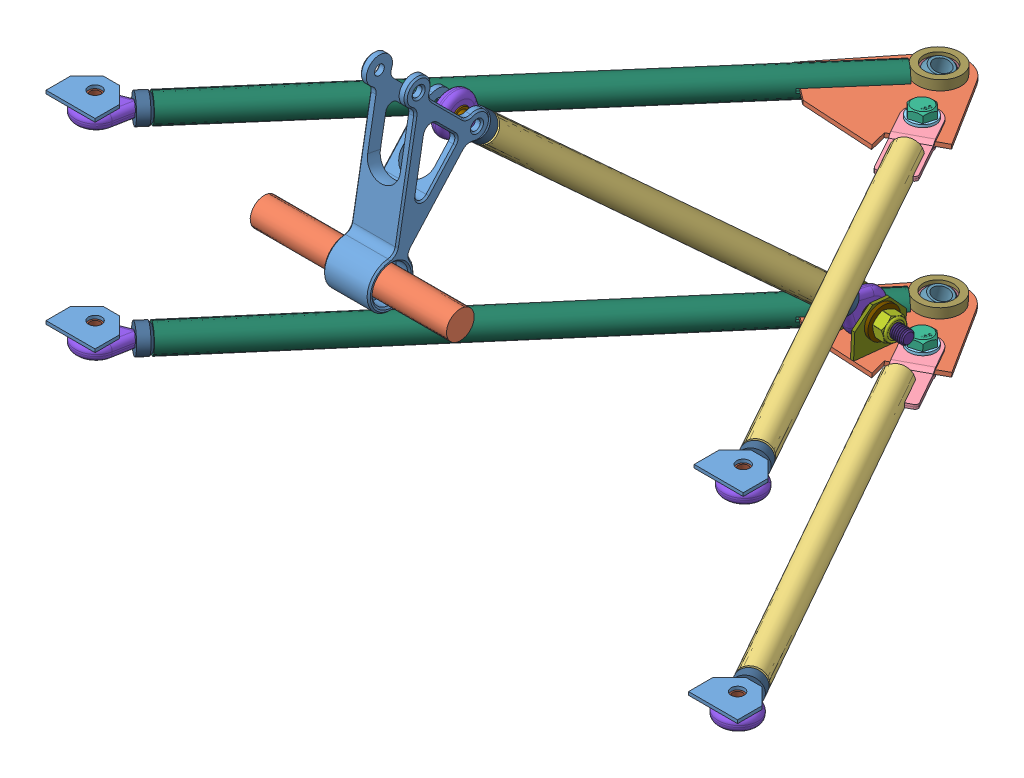
SolidWorks assembly Control Arms, Pushord, Bellcrank V6, configuration Default. Lengths in mm.
Overall size (449.35 312.63 431.67).
68 component instances, 21 part files, 29 mates.
Components (placement in the parent):
- frame connectors-10: frame connectors [Default] at (-357.6393 7.7366 39.1204) size (30 2 25)
- frame connectors-11: frame connectors [Default] at (38.6473 7.7366 39.1204) size (30 2 25)
- Upper Control Arm Assembly-1: Upper Control Arm Assembly [Default] at (-133.4882 -138.5087 -252.114) x (0.998299 0.002948 0.058228) z (-0.058303 0.05048 0.997022) size (425.46 42.68 337.86) (flexible)
  - Front Control Arm Plate-1: Front Control Arm Plate [Default] at origin size (91 2.5 76.52)
  - Rear Upper Control Arm-2: Rear Upper Control Arm [Default] at (102.2777 0 156.6502) x (-0.554844 0 -0.831954) z (0.831954 0 -0.554844) size (250 16 16)
  - Control Arm Link Plate-1: Control Arm Link Plate [Default] at (31.8652 1.25 43.6848) x (-0.554844 0 -0.831954) z (0.831954 0 -0.554844) size (54.1 2.5 20)
  - Control Arm Link Plate-2: Control Arm Link Plate [Default] at (31.8652 -1.25 43.6848) x (-0.554844 0 -0.831954) z (-0.831954 0 0.554844) size (54.1 2.5 20)
  - plain washer normal grade a_iso-1: plain washer normal grade a_iso [Washer ISO 7089 - 8] at (22.4051 2.5 29.5) x (0 -1 0) z (0.774417 0 0.632675) size (1.6 16 16)
  - 94863A205_High-Strength Class 10.9 Steel Hex Head Screw-1: 94863A205_High-Strength Class 10.9 Steel Hex Head Screw [94863A205] at (22.4051 4.1 29.5) x (0.632675 0 -0.774417) z (0 1 0) size (13 16.35 25.89)
  - 94645A111_High-Strength Steel Nylon-Insert Locknut-1: 94645A111_High-Strength Steel Nylon-Insert Locknut [94645A111] at (22.4051 -6.5 29.5) x (-0.772532 0 -0.634976) z (-0.634976 0 0.772532) size (13 8 14.93)
  - Link Insert Assembly-1: Link Insert Assembly [Default] at (147.8527 41.9532 248.8394) x (0.831954 0 -0.554844) z (0 -1 0) size (24 54 13.75) (flexible)
    - Link-1: Link [Default] at (13.2343 18.3157 41.9532) size (24 54 13.75)
    - Spherical Bearing Ball-1: Spherical Bearing Ball [Default] at (13.2343 47.8157 41.9532) x (0.025556 -0.043633 0.998721) z (0.479285 -0.876203 -0.050544) size (9 13.75 13.75)
  - Control Arm Insert-1: Control Arm Insert [Default] at (158.7294 0 241.2961) x (-0.831525 0.032128 0.554558) z (0.026729 0.999484 -0.017826) size (16 25 16)
  - 8mm Spehrical Bearing Insert-1: 8mm Spehrical Bearing Insert [Default] at (185.4125 6.4917 281.6051) x (0.944963 0.013733 -0.326889) z (-0.327164 0.048665 -0.943714) size (11 9 11)
  - Spherical Bearing Seat-1: Spherical Bearing Seat [Default] at (0 -0.3 0) size (30 15.1 30)
  - Wide Spherical Bearing-1: Wide Spherical Bearing [Default] at (-7.3247 -16.3877 13.3464) x (1 0 0) z (0 1 0) size (28.8 26.7 19.61) (flexible)
    - Wide Bearing Cage-1: Wide Bearing Cage [Default] at (7.3247 13.3464 16.0877) size (22 22 10.5)
    - Wide Ball-1: Wide Ball [Default] at (7.3247 13.3464 16.0877) x (-0.815772 0.552249 0.171862) z (0.221159 0.02328 0.97496) size (19.04 19.04 14)
  - Front Upper Control Arm-1: Front Upper Control Arm [Default] at (-100.6334 0 146.8287) x (0.559193 0 -0.829038) z (0.829038 0 0.559193) size (330 16 16)
  - Link Insert Assembly-2: Link Insert Assembly [Default] at (-191.0018 41.9532 257.1385) x (0.829038 0 0.559193) z (0 -1 0) size (24 54 13.75) (flexible)
    - Link-1: Link [Default] at (13.2343 18.3157 41.9532) size (24 54 13.75)
    - Spherical Bearing Ball-1: Spherical Bearing Ball [Default] at (13.2343 47.8157 41.9532) x (-0.030672 -0.040201 0.998721) z (-0.682409 -0.729237 -0.050311) size (9 13.75 13.75)
  - Control Arm Insert-2: Control Arm Insert [Default] at (-179.8953 0 264.3393) x (-0.82861 0.032128 -0.558904) z (0.026635 0.999484 0.017966) size (16 25 16)
  - 8mm Spehrical Bearing Insert-2: 8mm Spehrical Bearing Insert [Default] at (-206.7491 6.4917 304.5081) x (-0.995047 0.007946 -0.099088) z (-0.099363 -0.049938 0.993797) size (11 9 11)
  - Push Rod Upper Control Arm Bracket-1: Push Rod Upper Control Arm Bracket [Default] at (10.7762 13.75 44.5) x (0 0 1) z (0 -1 0) size (30 2 25)
  - Push Rod Upper Control Arm Bracket-2: Push Rod Upper Control Arm Bracket [Default] at (-11.2238 13.75 44.5) x (0 0 1) z (0 -1 0) size (30 2 25)
- frame connectors-14: frame connectors [Default] at (-357.6393 -114.2634 39.1204) size (30 2 25)
- frame connectors-15: frame connectors [Default] at (35.1906 -114.2634 39.1204) size (30 2 25)
- Lower Control Arm Assembly-4: Lower Control Arm Assembly [Default] at (-132.0035 -16.4507 -250.9682) x (0.997989 0.003206 0.063314) z (-0.063395 0.050464 0.996712) size (428.79 25.89 337.86) (flexible)
  - Front Control Arm Plate-1: Front Control Arm Plate [Default] at origin size (91 2.5 76.52)
  - Rear Upper Control Arm-2: Rear Upper Control Arm [Default] at (105.6055 0 154.4308) x (-0.554844 0 -0.831954) z (0.831954 0 -0.554844) size (250 16 16)
  - Control Arm Link Plate-1: Control Arm Link Plate [Default] at (31.8652 1.25 43.6848) x (-0.554844 0 -0.831954) z (0.831954 0 -0.554844) size (54.1 2.5 20)
  - Control Arm Link Plate-2: Control Arm Link Plate [Default] at (31.8652 -1.25 43.6848) x (-0.554844 0 -0.831954) z (-0.831954 0 0.554844) size (54.1 2.5 20)
  - plain washer normal grade a_iso-1: plain washer normal grade a_iso [Washer ISO 7089 - 8] at (22.4051 2.5 29.5) x (0 -1 0) z (0.774417 0 0.632675) size (1.6 16 16)
  - 94863A205_High-Strength Class 10.9 Steel Hex Head Screw-1: 94863A205_High-Strength Class 10.9 Steel Hex Head Screw [94863A205] at (22.4051 4.1 29.5) x (0.632675 0 -0.774417) z (0 1 0) size (13 16.35 25.89)
  - 94645A111_High-Strength Steel Nylon-Insert Locknut-1: 94645A111_High-Strength Steel Nylon-Insert Locknut [94645A111] at (22.4051 -6.5 29.5) x (-0.783807 0 -0.621005) z (-0.621005 0 0.783807) size (13 8 14.93)
  - Link Insert Assembly-1: Link Insert Assembly [Default] at (151.1806 41.9532 246.62) x (0.831954 0 -0.554844) z (0 -1 0) size (24 54 13.75) (flexible)
    - Link-1: Link [Default] at (13.2343 18.3157 41.9532) size (24 54 13.75)
    - Spherical Bearing Ball-1: Spherical Bearing Ball [Default] at (13.2343 47.8157 41.9532) x (0.025333 -0.043762 0.998721) z (-0.222587 0.973715 0.048313) size (9 13.75 13.75)
  - Control Arm Insert-1: Control Arm Insert [Default] at (162.0573 0 239.0767) x (-0.831525 0.032128 0.554558) z (0.026729 0.999484 -0.017826) size (16 25 16)
  - 8mm Spehrical Bearing Insert-1: 8mm Spehrical Bearing Insert [Default] at (188.742 6.4917 279.3856) x (0.571791 -0.043231 0.81926) z (0.820393 0.026229 -0.571198) size (11 9 11)
  - Spherical Bearing Seat-1: Spherical Bearing Seat [Default] at (0 -0.3 0) size (30 15.1 30)
  - Wide Spherical Bearing-1: Wide Spherical Bearing [Default] at (-7.3247 -16.3877 13.3464) x (1 0 0) z (0 1 0) size (28.19 26.12 19.54) (flexible)
    - Wide Bearing Cage-1: Wide Bearing Cage [Default] at (7.3247 13.3464 16.0877) size (22 22 10.5)
    - Wide Ball-1: Wide Ball [Default] at (7.3247 13.3464 16.0877) x (-0.86201 0.472657 0.183125) z (0.220909 0.025145 0.97497) size (19.04 19.04 14)
  - Front Upper Control Arm-1: Front Upper Control Arm [Default] at (-100.6334 0 146.8287) x (0.559193 0 -0.829038) z (0.829038 0 0.559193) size (330 16 16)
  - Link Insert Assembly-2: Link Insert Assembly [Default] at (-191.0018 41.9532 257.1385) x (0.829038 0 0.559193) z (0 -1 0) size (24 54 13.75) (flexible)
    - Link-1: Link [Default] at (13.2343 18.3157 41.9532) size (24 54 13.75)
    - Spherical Bearing Ball-1: Spherical Bearing Ball [Default] at (13.2343 47.8157 41.9532) x (-0.030877 -0.040044 0.998721) z (-0.746265 -0.663792 -0.049687) size (9 13.75 13.75)
  - Control Arm Insert-2: Control Arm Insert [Default] at (-179.8953 0 264.3393) x (-0.82861 0.032128 -0.558904) z (0.026635 0.999484 0.017966) size (16 25 16)
  - 8mm Spehrical Bearing Insert-2: 8mm Spehrical Bearing Insert [Default] at (-206.7474 6.4917 304.508) x (-0.997262 0.006921 -0.07363) z (-0.073885 -0.05009 0.996008) size (11 9 11)
- M8 45mm hex bolt-1: M8 45mm hex bolt [91310A132] at (-131.2946 -120.019 -208.2889) x (0.040016 -0.760983 -0.647536) z (-0.998299 -0.002948 -0.058228) size (13 14.81 50.91)
- flat washer narrow_am-1: flat washer narrow_am [B18.22M - Plain washer, 8 mm, narrow] at (-148.2857 -120.0692 -209.28) x (0.998299 0.002948 0.058228) z (-0.058088 -0.035284 0.997688) size (2.3 18.8 18.8)
- Bell Crank-1: Bell Crank [Default] at (-135.2518 51.3365 94.2178) x (0.000011 0.706585 0.707629) z (-0.000012 -0.707629 0.706585) size (76.38 28 99.9)
- FRAME ROD-1: FRAME ROD [Default] at (-139.199 51.3366 94.2178) x (-0.000007 -0.442227 0.896903) z (-1 0.000016 0) size (17 17 120)
- 94645A111_High-Strength Steel Nylon-Insert Locknut-1: 94645A111_High-Strength Steel Nylon-Insert Locknut [94645A111] at (-118.0372 -119.9799 -207.5156) x (0.056556 0.193662 -0.979437) z (0.014164 -0.981064 -0.193165) size (13 8 14.93)
- flat washer narrow_am-3: flat washer narrow_am [B18.22M - Plain washer, 8 mm, narrow] at (-122.0304 -119.9917 -207.7486) x (0.998299 0.002948 0.058228) z (-0.058088 -0.035284 0.997688) size (2.3 18.8 18.8)
- Front Push Rod Assembly-2: Front Push Rod Assembly [Default] at (-347.044 -64.2436 109.6171) x (-0.000011 -0.675191 -0.737643) z (0.999306 -0.027492 0.025149) size (363.6 24.5 20.9) (flexible)
  - Front Push Rod-1: Front Push Rod [Default] at (102.5362 181.4229 205.1752) size (290 16 16)
  - Control Arm Insert-1: Control Arm Insert [Default] at (224.2796 181.4229 205.1752) x (0 -1 0) z (0 0 1) size (16 25 16)
  - Control Arm Insert-2: Control Arm Insert [Default] at (-19.2072 181.4229 205.1752) x (0 -0.381849 0.924225) z (0 -0.924225 -0.381849) size (16 25 16)
  - Link Insert Assembly-1: Link Insert Assembly [Default] at (-19.4481 196.2107 246.6063) x (0 -0.999306 0.037247) z (0 -0.037247 -0.999306) size (24 54 13.75) (flexible)
    - Link-1: Link [Default] at (13.2343 18.3157 41.9532) size (24 54 13.75)
    - Spherical Bearing Ball-1: Spherical Bearing Ball [Default] at (13.2343 47.8157 41.9532) x (0 0 1) z (0.293221 -0.956045 0) size (9 13.75 13.75)
  - Link Insert Assembly-2: Link Insert Assembly [Default] at (224.5204 194.6572 163.222) x (0 -1 0) z (0 0 1) size (24 54 13.75) (flexible)
    - Link-1: Link [Default] at (13.2343 18.3157 41.9532) size (24 54 13.75)
    - Spherical Bearing Ball-1: Spherical Bearing Ball [Default] at (13.2343 47.8157 41.9532) x (-0.000081 -0.044953 0.998989) z (0.935805 -0.352165 -0.015771) size (9 13.75 13.75)
Mates (geometry in assembly coordinates):
- Concentric18: concentric aligned: cylinder of frame connectors-10 through (-357.6393 8.7366 39.1204) axis (0 -1 0) radius 4; cylinder of frame connectors-14 through (-357.6393 -113.2634 39.1204) axis (0 -1 0) radius 4
- Coincident27: coincident aligned: plane of frame connectors-10 through (-372.6393 8.7366 54.1204) normal (0 0 1); plane of frame connectors-14 through (-372.6393 -113.2634 54.1204) normal (0 0 1)
- Distance2: distance = 120 mm anti-aligned: plane of frame connectors-14 through (-357.6393 -113.2634 39.1204) normal (0 1 0); plane of frame connectors-10 through (-357.6393 6.7366 39.1204) normal (0 -1 0)
- Concentric19: concentric aligned: cylinder of Upper Control Arm Assembly-1/8mm Spehrical Bearing Insert-2 through (-357.6393 -117.2634 39.1204) axis (0 -1 0) radius 3; cylinder of frame connectors-14 through (-357.6393 -113.2634 39.1204) axis (0 -1 0) radius 4
- Coincident29: coincident anti-aligned: plane of Upper Control Arm Assembly-1/8mm Spehrical Bearing Insert-2 through (-352.2076 -115.2634 39.9847) normal (0 1 0); plane of frame connectors-14 through (-357.6393 -115.2634 39.1204) normal (0 -1 0)
- Coincident30: coincident aligned: plane of frame connectors-14 through (-372.6393 -113.2634 54.1204) normal (0 0 1); plane of frame connectors-15 through (20.1906 -113.2634 54.1204) normal (0 0 1)
- Coincident31: coincident aligned: plane of frame connectors-14 through (-357.6393 -113.2634 39.1204) normal (0 1 0); plane of frame connectors-15 through (35.1906 -113.2634 39.1204) normal (0 1 0)
- Concentric21: concentric aligned: cylinder of frame connectors-10 through (-357.6393 8.7366 39.1204) axis (0 -1 0) radius 4; circle of Lower Control Arm Assembly-4/8mm Spehrical Bearing Insert-2
- Coincident33: coincident anti-aligned: plane of frame connectors-10 through (-357.6393 6.7366 39.1204) normal (0 -1 0); plane of Lower Control Arm Assembly-4/8mm Spehrical Bearing Insert-2 through (-352.191 6.7366 39.8732) normal (0 1 0)
- Coincident38: coincident anti-aligned: plane of Upper Control Arm Assembly-1/8mm Spehrical Bearing Insert-1 through (29.8973 -115.2634 40.6141) normal (0 1 0); plane of frame connectors-15 through (35.1906 -115.2634 39.1204) normal (0 -1 0)
- Concentric22: concentric aligned: cylinder of Upper Control Arm Assembly-1/8mm Spehrical Bearing Insert-1 through (35.1906 -117.2634 39.1204) axis (0 -1 0) radius 3; cylinder of frame connectors-15 through (35.1906 -113.2634 39.1204) axis (0 -1 0) radius 4
- Coincident39: coincident aligned: plane of frame connectors-10 through (-372.6393 8.7366 54.1204) normal (0 0 1); plane of frame connectors-11 through (23.6473 8.7366 54.1204) normal (0 0 1)
- Coincident40: coincident aligned: plane of frame connectors-10 through (-357.6393 8.7366 39.1204) normal (0 1 0); plane of frame connectors-11 through (38.6473 8.7366 39.1204) normal (0 1 0)
- Concentric23: concentric aligned: cylinder of frame connectors-11 through (38.6473 8.7366 39.1204) axis (0 -1 0) radius 4; cylinder of Lower Control Arm Assembly-4/8mm Spehrical Bearing Insert-1 through (38.6473 4.7366 39.1204) axis (0 -1 0) radius 3
- Coincident41: coincident anti-aligned: plane of frame connectors-11 through (38.6473 6.7366 39.1204) normal (0 -1 0); plane of Lower Control Arm Assembly-4/8mm Spehrical Bearing Insert-1 through (35.7944 6.7366 34.4182) normal (0 1 0)
- Parallel9: parallel aligned: plane of Upper Control Arm Assembly-1/Front Control Arm Plate-1 through (-133.4872 -137.2612 -252.1937) normal (0 0.998721 -0.050566); plane of Lower Control Arm Assembly-4/Front Control Arm Plate-1 through (-132.0025 -15.2032 -251.0479) normal (0 0.998721 -0.050566)
- Concentric24: concentric anti-aligned: cylinder of Upper Control Arm Assembly-1/Push Rod Upper Control Arm Bracket-2 through (-148.2857 -120.0692 -209.28) axis (0.998299 0.002948 0.058228) radius 4; cylinder of flat washer narrow_am-1 through (-183.1513 -120.1722 -211.3136) axis (-0.998299 -0.002948 -0.058228) radius 4.56
- Coincident42: coincident anti-aligned: plane of Upper Control Arm Assembly-1/Push Rod Upper Control Arm Bracket-2 through (-148.2857 -122.566 -209.1535) normal (-0.998299 -0.002948 -0.058228); plane of flat washer narrow_am-1 through (-148.3085 -115.5121 -209.1201) normal (0.998299 0.002948 0.058228)
- Concentric25: concentric anti-aligned: cylinder of Upper Control Arm Assembly-1/Push Rod Upper Control Arm Bracket-2 through (-148.2857 -120.0692 -209.28) axis (0.998299 0.002948 0.058228) radius 4; cylinder of M8 45mm hex bolt-1 through (-151.1109 -120.0776 -209.4447) axis (-0.998299 -0.002948 -0.058228) radius 5.7528
- Coincident43: coincident anti-aligned: plane of M8 45mm hex bolt-1 through (-150.5818 -120.076 -209.4139) normal (0.998299 0.002948 0.058228); plane of flat washer narrow_am-1 through (-150.6287 -110.6819 -209.0844) normal (-0.998299 -0.002948 -0.058228)
- Concentric35: concentric anti-aligned: cylinder of Bell Crank-1 through (-121.2518 51.3363 94.2178) axis (-1 0.000016 0) radius 8.5; cylinder of FRAME ROD-1 through (-199.199 51.3376 94.2178) axis (1 -0.000016 0) radius 8.5
- Concentric36: concentric aligned: cylinder of M8 45mm hex bolt-1 through (-151.1109 -120.0776 -209.4447) axis (-0.998299 -0.002948 -0.058228) radius 5.7528; cylinder of 94645A111_High-Strength Steel Nylon-Insert Locknut-1 through (-122.0304 -119.9917 -207.7486) axis (-0.998299 -0.002948 -0.058228) radius 6.5
- Concentric37: concentric aligned: cylinder of M8 45mm hex bolt-1 through (-151.1109 -120.0776 -209.4447) axis (-0.998299 -0.002948 -0.058228) radius 5.7528; cylinder of flat washer narrow_am-3 through (-156.896 -120.0946 -209.7822) axis (-0.998299 -0.002948 -0.058228) radius 4.56
- Coincident56: coincident anti-aligned: plane of Upper Control Arm Assembly-1/Push Rod Upper Control Arm Bracket-1 through (-124.3265 -122.4953 -207.7561) normal (0.998299 0.002948 0.058228); plane of flat washer narrow_am-3 through (-124.3735 -110.6044 -207.553) normal (-0.998299 -0.002948 -0.058228)
- Coincident57: coincident anti-aligned: plane of 94645A111_High-Strength Steel Nylon-Insert Locknut-1 through (-122.0304 -119.9917 -207.7486) normal (-0.998299 -0.002948 -0.058228); plane of flat washer narrow_am-3 through (-122.0532 -115.4345 -207.5887) normal (0.998299 0.002948 0.058228)
- Concentric38: concentric aligned: circle of Upper Control Arm Assembly-1/Push Rod Upper Control Arm Bracket-2; cylinder of Front Push Rod Assembly-2/Link Insert Assembly-2/Spherical Bearing Ball-1 through (-142.1196 -120.051 -208.9203) axis (-0.998299 -0.002948 -0.058228) radius 4
- Distance4: distance = 6 mm anti-aligned: plane of Front Push Rod Assembly-2/Link Insert Assembly-1/Link-1 through (-131.2508 109.264 41.9837) normal (1 -0.000016 0); plane of Bell Crank-1 through (-125.2512 88.0434 51.8676) normal (-1 0.000016 0)
- Distance5: distance = 42.0528 mm aligned: plane of Bell Crank-1 through (-121.2518 51.3363 94.2178) normal (1 -0.000016 0); plane of FRAME ROD-1 through (-79.199 51.3356 94.2178) normal (1 -0.000016 0)
- Concentric42: concentric anti-aligned: cylinder of Bell Crank-1 through (-121.2508 109.2638 41.9837) axis (-1 0.000016 0) radius 3; cylinder of Front Push Rod Assembly-2/Link Insert Assembly-1/Spherical Bearing Ball-1 through (-128.374 109.264 41.9837) axis (1 -0.000016 0) radius 4
